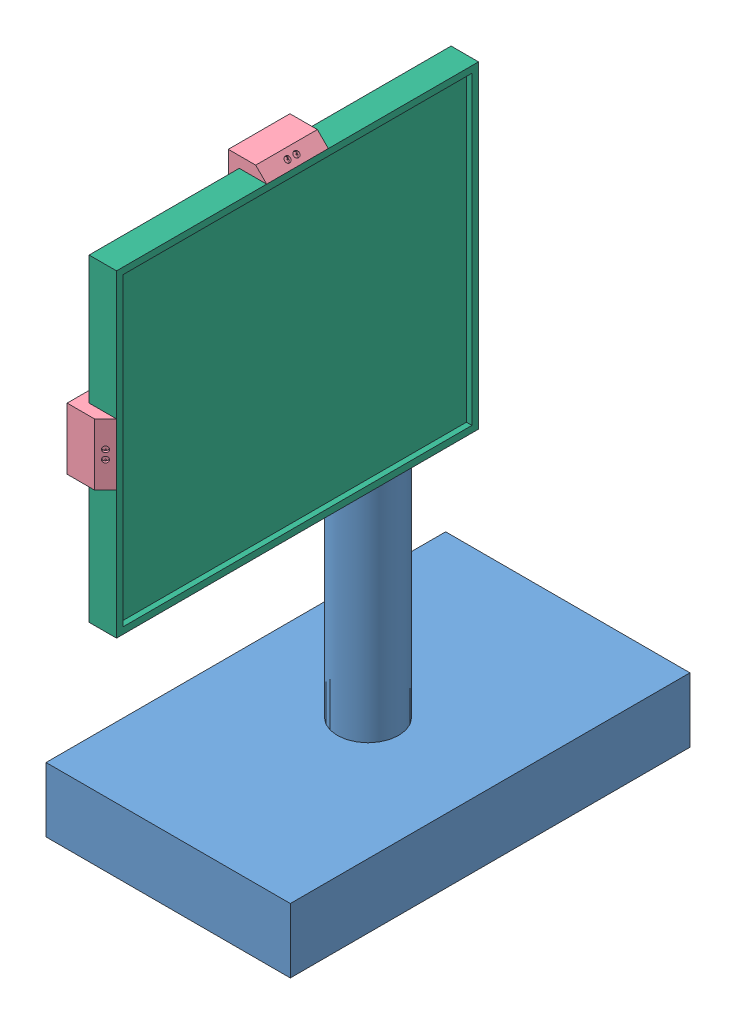
SolidWorks assembly painel solar, configuration Default. Lengths in mm.
Overall size (222.68 613.4 498.64).
8 component instances, 6 part files, 17 mates.
Components (placement in the parent):
- Part3-1: Part3 [Default] at (97.0718 74.0373 338.8051) size (222.68 408.8 364.28)
- motor-1: motor [Default] at (97.0718 365.5373 345.8051) x (1 0 0) z (0 1 0) size (37 37 79.5)
- suporte1b-1: suporte1b [Default] at (97.0718 473.6373 366.9051) size (56.2 77.7 117.5)
- suporte2b-1: suporte2b [Default] at (97.0718 473.6373 428.2051) size (105.34 310 350)
- motor-2: motor [Default] at (97.0718 466.6373 369.7051) size (37 37 79.5)
- tampa eletrica-1: tampa eletrica [Default] at (66.4718 473.6373 480.3051) x (0 0 -1) z (1 0 0) size (56.2 56.2 5)
- tampa eletrica-2: tampa eletrica [Default] at (97.0718 473.6373 308.2051) size (56.2 56.2 5)
- PainelSolar-1: PainelSolar [Default] at (149.3118 473.6373 480.3051) x (0 1 0) z (1 0 0) size (290 330 25)
Mates (geometry in assembly coordinates):
- Concentric2: concentric: cylinder of assembly; cylinder of assembly; cylinder of Part3-1 through (97.0718 365.2373 345.8051) axis (0 1 0) radius 18.6; cylinder of motor-1 through (97.0718 424.0373 345.8051) axis (0 -1 0) radius 18.5
- Coincident2: coincident: plane of assembly; plane of assembly; plane of Part3-1 through (97.0718 424.0373 338.8051) normal (0 1 0); plane of motor-1 through (97.0718 424.0373 345.8051) normal (0 1 0)
- Coincident3: coincident: plane of assembly; plane of assembly; plane of Part3-1 through (97.0718 424.0373 338.8051) normal (0 1 0); plane of suporte1b-1 through (97.0718 424.0373 338.8051) normal (0 -1 0)
- Concentric3: concentric: cylinder of assembly; cylinder of assembly; cylinder of Part3-1 through (97.0718 424.0373 338.8051) axis (0 -1 0) radius 28.1; cylinder of suporte1b-1 through (97.0718 424.0373 338.8051) axis (0 1 0) radius 28.1
- Concentric4: concentric: cylinder of assembly; cylinder of assembly; cylinder of suporte1b-1 through (97.0718 466.6373 369.4051) axis (0 0 1) radius 18.6; cylinder of motor-2 through (97.0718 466.6373 428.2051) axis (0 0 -1) radius 18.5
- Coincident4: coincident: plane of assembly; plane of assembly; plane of suporte1b-1 through (97.0718 473.6373 428.2051) normal (0 0 1); plane of motor-2 through (97.0718 466.6373 428.2051) normal (0 0 1)
- Coincident5: coincident: plane of assembly; plane of assembly; plane of suporte1b-1 through (97.0718 473.6373 428.2051) normal (0 0 1); plane of suporte2b-1 through (97.0718 473.6373 428.2051) normal (0 0 -1)
- Concentric5: concentric: cylinder of assembly; cylinder of assembly; cylinder of suporte1b-1 through (97.0718 473.6373 428.2051) axis (0 0 -1) radius 28.1; cylinder of suporte2b-1 through (97.0718 473.6373 452.2051) axis (0 0 -1) radius 28.1
- Coincident6: coincident: plane of assembly; plane of assembly; plane of suporte1b-1 through (97.0718 473.6373 310.7051) normal (0 0 -1); plane of tampa eletrica-2 through (97.0718 473.6373 310.7051) normal (0 0 1)
- Coincident7: coincident: plane of assembly; plane of assembly; plane of suporte1b-1 through (125.1718 501.7373 310.7051) normal (0 1 0); plane of tampa eletrica-2 through (68.9718 501.7373 310.7051) normal (0 1 0)
- Coincident8: coincident: plane of assembly; plane of assembly; plane of suporte1b-1 through (68.9718 445.5373 310.7051) normal (-1 0 0); plane of tampa eletrica-2 through (68.9718 445.5373 310.7051) normal (-1 0 0)
- Coincident9: coincident: plane of assembly; plane of assembly; plane of suporte2b-1 through (68.9718 445.5373 508.4051) normal (-1 0 0); plane of tampa eletrica-1 through (68.9718 473.6373 480.3051) normal (1 0 0)
- Coincident10: coincident: plane of assembly; plane of assembly; plane of suporte2b-1 through (97.0718 473.6373 508.4051) normal (0 0 1); plane of tampa eletrica-1 through (68.9718 445.5373 508.4051) normal (0 0 1)
- Coincident11: coincident: plane of assembly; plane of assembly; plane of suporte2b-1 through (68.9718 501.7373 508.4051) normal (0 1 0); plane of tampa eletrica-1 through (68.9718 501.7373 508.4051) normal (0 1 0)
- Coincident12: coincident: plane of assembly; plane of assembly; plane of suporte2b-1 through (174.3118 501.7373 645.3051) normal (0 0 -1); plane of PainelSolar-1 through (174.3118 328.6373 645.3051) normal (0 0 1)
- Coincident13: coincident: plane of assembly; plane of assembly; plane of suporte2b-1 through (149.3118 473.6373 428.2051) normal (1 0 0); plane of PainelSolar-1 through (149.3118 473.6373 480.3051) normal (-1 0 0)
- Coincident14: coincident: plane of assembly; plane of assembly; plane of suporte2b-1 through (174.3118 328.6373 508.4051) normal (0 1 0); plane of PainelSolar-1 through (174.3118 328.6373 315.3051) normal (0 -1 0)
